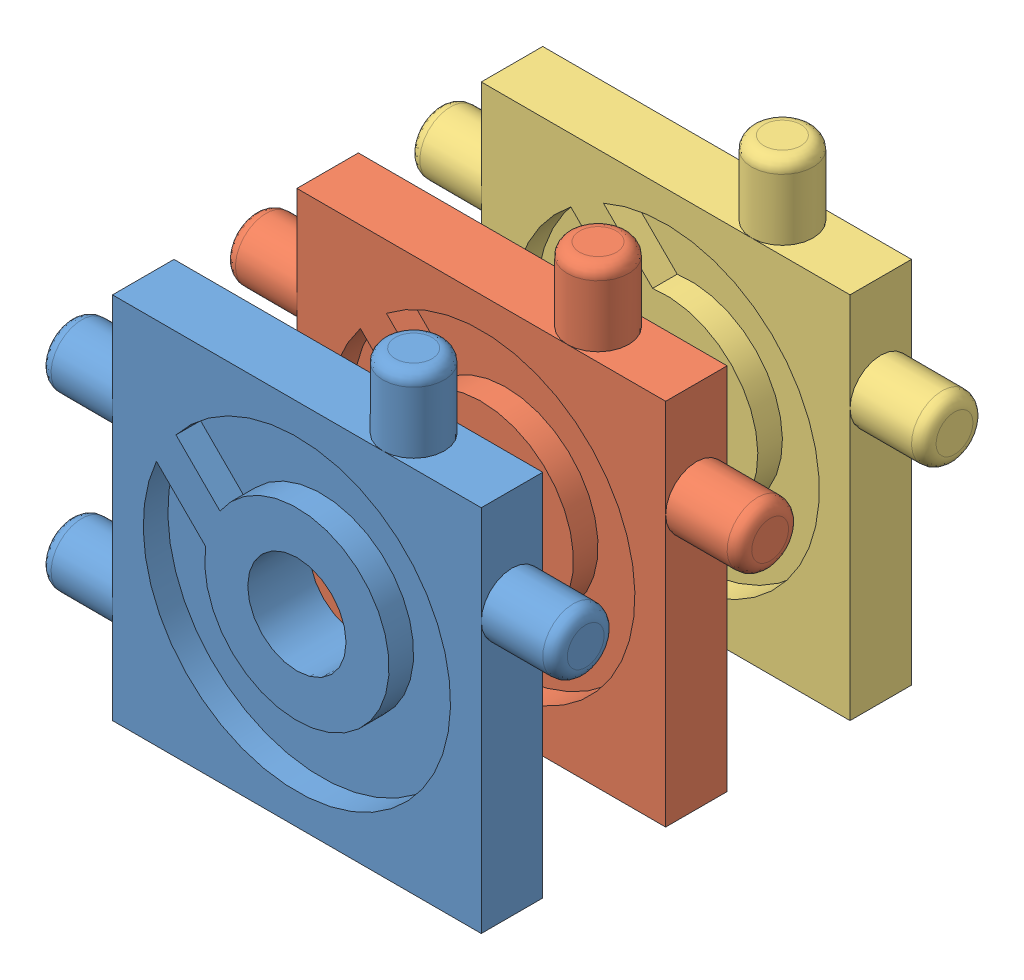
SolidWorks assembly Assemblage1, configuration Défaut. Lengths in mm.
Overall size (42 36 37.5).
3 component instances, 3 part files, 6 mates.
Components (placement in the parent):
- palet 1-1: palet 1 [Défaut] at (-3.3605 -0.0995 42) size (42 36 7.5)
- palet 2-1: palet 2 [Défaut] at (-3.3605 -0.0995 27) size (42 36 7.5)
- palet 3-2: palet 3 [Défaut] at (-3.3605 -0.0995 12) size (42 36 7.5)
Mates (geometry in assembly coordinates):
- Coaxiale3: concentric aligned: cylinder of palet 1-1 through (-3.3605 -0.0995 42) axis (0 0 1) radius 4; cylinder of palet 2-1 through (-3.3605 -0.0995 27) axis (0 0 1) radius 4
- Coaxiale4: concentric aligned: cylinder of palet 1-1 through (-3.3605 -0.0995 42) axis (0 0 1) radius 4; cylinder of palet 3-2 through (-3.3605 -0.0995 12) axis (0 0 1) radius 4
- Distance3: distance = 10 mm anti-aligned: plane of palet 1-1 through (-3.3605 -0.0995 42) normal (0 0 -1); plane of palet 2-1 through (-3.3605 -0.0995 32) normal (0 0 1)
- Distance4: distance = 10 mm anti-aligned: plane of palet 2-1 through (-3.3605 -0.0995 27) normal (0 0 -1); plane of palet 3-2 through (-3.3605 -0.0995 17) normal (0 0 1)
- Coïncidente8: coincident anti-aligned: plane of palet 1-1 through (-13.26 7.6787 39.5) normal (0.707107 0.707107 0); plane of palet 2-1 through (-13.26 7.6787 24.5) normal (-0.707107 -0.707107 0)
- Coïncidente9: coincident anti-aligned: plane of palet 2-1 through (-11.1387 9.8 24.5) normal (0.707107 0.707107 0); plane of palet 3-2 through (-11.4923 10.1536 9.5) normal (-0.707107 -0.707107 0)
